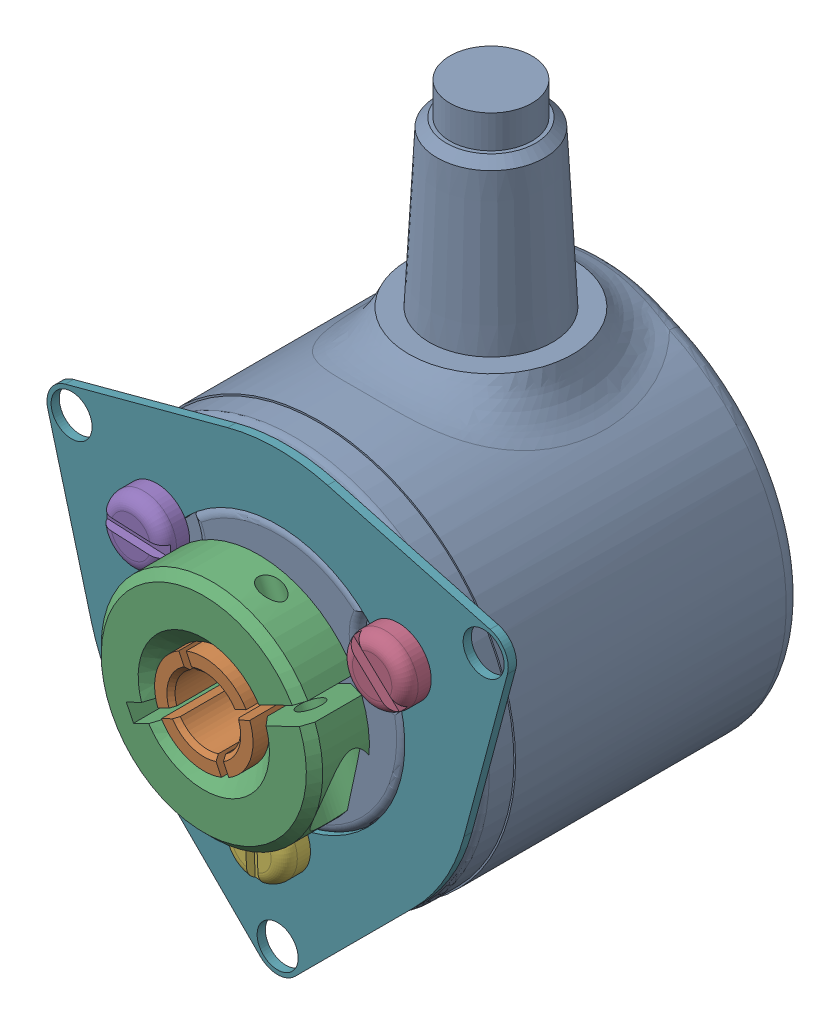
SolidWorks assembly Codeur_2MRH, configuration Default. Lengths in mm.
Overall size (38.09 42.8 24.5).
8 component instances, 6 part files, 16 mates.
Components (placement in the parent):
- corps_codeur_2MRH-1: corps_codeur_2MRH [Default] at (3.2886 -2.5929 -14.3048) size (24 36.75 20.04)
- mandrin_codeur_2MRH-1: mandrin_codeur_2MRH [Default] at (3.2886 -2.5929 -3.8048) x (-0.434638 0.900605 0) z (0 0 1) size (6 6 14)
- bague_codeur_2MRH-1: bague_codeur_2MRH [Default] at (3.2886 -2.5929 5.6952) x (0.434638 -0.900605 0) z (0 0 1) size (13.5 13.48 4.5)
- Socket Head Cap Screw_AM-1: Socket Head Cap Screw_AM [B18.3.1M - 1.6 x 0.35 x 5 Hex SHCS -- 5NHX] at (9.1066 -4.3376 7.9452) x (-0.434638 0.900605 0) z (0 0 1) (suppressed, hidden)
- Vis_fendue_tete_bombee_M2_L5-1: Vis_fendue_tete_bombee_M2_L5 [B18.6.7M - M2 x 0.4 x 4 Slotted PHMS --4N] at (10.6498 1.6571 7.2952) x (0 0 -1) z (0.728333 -0.685223 0) size (5.65 4 4)
- Vis_fendue_tete_bombee_M2_L5-2: Vis_fendue_tete_bombee_M2_L5 [B18.6.7M - M2 x 0.4 x 4 Slotted PHMS --4N] at (-4.0726 1.6571 7.2952) x (0 0 -1) z (0.998972 -0.045336 0) size (5.65 4 4)
- Vis_fendue_tete_bombee_M2_L5-3: Vis_fendue_tete_bombee_M2_L5 [B18.6.7M - M2 x 0.4 x 4 Slotted PHMS --4N] at (3.2886 -11.0929 7.2952) x (0 0 -1) z (-0.043781 0.999041 0) size (5.65 4 4)
- Bride_membrane-1: Bride_membrane [Default] at (3.2886 -2.5929 5.6952) x (0.5 0.866025 0) z (-0.866025 0.5 0) size (28.11 0.5 27.75)
Mates (geometry in assembly coordinates):
- Coaxiale2: concentric anti-aligned: cylinder of corps_codeur_2MRH-1; cylinder of mandrin_codeur_2MRH-1
- Coïncidente1: coincident anti-aligned: plane of corps_codeur_2MRH-1 through (3.2886 -2.5929 -3.8048) normal (0 0 1); plane of mandrin_codeur_2MRH-1 through (3.2886 -2.5929 -3.8048) normal (0 0 -1)
- Coïncidente2: coincident anti-aligned: plane of corps_codeur_2MRH-1 through (3.2886 -2.5929 5.6952) normal (0 0 1); plane of bague_codeur_2MRH-1 through (3.2886 -2.5929 5.6952) normal (0 0 -1)
- Coaxiale3: concentric aligned: cylinder of mandrin_codeur_2MRH-1; cylinder of bague_codeur_2MRH-1
- Parallèle1: parallel aligned: plane of mandrin_codeur_2MRH-1 through (3.4051 -2.2591 0.1952) normal (0.434638 -0.900605 0); plane of bague_codeur_2MRH-1 through (9.1337 0.7831 5.6942) normal (0.434638 -0.900605 0)
- Coaxiale41: concentric anti-aligned: cylinder of bague_codeur_2MRH-1; cylinder of Socket Head Cap Screw_AM-1
- Coïncidente41: coincident anti-aligned: plane of bague_codeur_2MRH-1 through (8.4112 -2.8966 7.9452) normal (0.434638 -0.900605 0); plane of Socket Head Cap Screw_AM-1 through (7.0603 -3.5486 7.9452) normal (-0.434638 0.900605 0)
- Coaxiale81: concentric aligned: cylinder of corps_codeur_2MRH-1; cylinder of Vis_fendue_tete_bombee_M2_L5-1
- Coaxiale91: concentric aligned: cylinder of corps_codeur_2MRH-1; cylinder of Vis_fendue_tete_bombee_M2_L5-2
- Coaxiale101: concentric aligned: cylinder of corps_codeur_2MRH-1; cylinder of Vis_fendue_tete_bombee_M2_L5-3
- Coïncidente102: coincident anti-aligned: plane of corps_codeur_2MRH-1 through (3.2886 -2.5929 5.1952) normal (0 0 1); plane of Bride_membrane-1 through (3.2886 -2.5929 5.1952) normal (0 0 -1)
- Coïncidente103: coincident aligned: circle of corps_codeur_2MRH-1; cylinder of Bride_membrane-1
- Coaxiale102: concentric aligned: cylinder of corps_codeur_2MRH-1; cylinder of Bride_membrane-1
- Coïncidente104: coincident anti-aligned: plane of Vis_fendue_tete_bombee_M2_L5-2 through (-4.0273 2.6561 5.6952) normal (0 0 -1); plane of Bride_membrane-1 through (3.2886 -2.5929 5.6952) normal (0 0 1)
- Coïncidente105: coincident anti-aligned: plane of Vis_fendue_tete_bombee_M2_L5-1 through (11.335 2.3854 5.6952) normal (0 0 -1); plane of Bride_membrane-1 through (3.2886 -2.5929 5.6952) normal (0 0 1)
- Coïncidente106: coincident anti-aligned: plane of Vis_fendue_tete_bombee_M2_L5-3 through (2.2896 -11.1367 5.6952) normal (0 0 -1); plane of Bride_membrane-1 through (3.2886 -2.5929 5.6952) normal (0 0 1)
